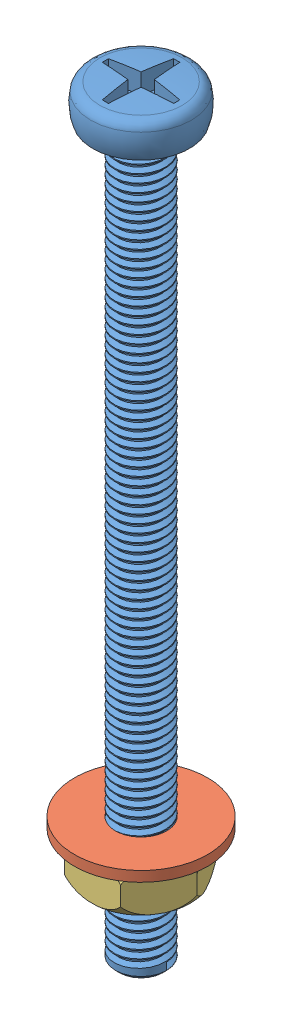
SolidWorks assembly Screw 5mm total Asm, configuration Default. Lengths in mm.
Overall size (13.87 74.49 13.87).
3 component instances, 3 part files, 3 mates.
Components (placement in the parent):
- Screw 5mm-1: Screw 5mm [Default] at (4.2075 23.5222 21.8965) size (10 74.49 10)
- Ross 5 mm-1: Ross 5 mm [Default] at (4.2075 -35.5507 21.8965) x (0.997618 0 0.068982) z (-0.068982 0 0.997618) size (13 1 13)
- Nut 5 mm-1: Nut 5 mm [Default] at (4.2075 -38.5507 21.8965) size (11.46 4.49 10.93)
Mates (geometry in assembly coordinates):
- Coincident1: coincident aligned: circle of Ross 5 mm-1; circle of Nut 5 mm-1
- Concentric1: concentric aligned: cylinder of Screw 5mm-1 through (4.2075 -47.7507 21.8965) axis (0 1 0) radius 2.5; cylinder of Ross 5 mm-1 through (4.2075 -36.5507 21.8965) axis (0 1 0) radius 2.5
- Coincident2: coincident anti-aligned: plane of Ross 5 mm-1 through (4.2075 -35.5507 21.8965) normal (0 1 0)
